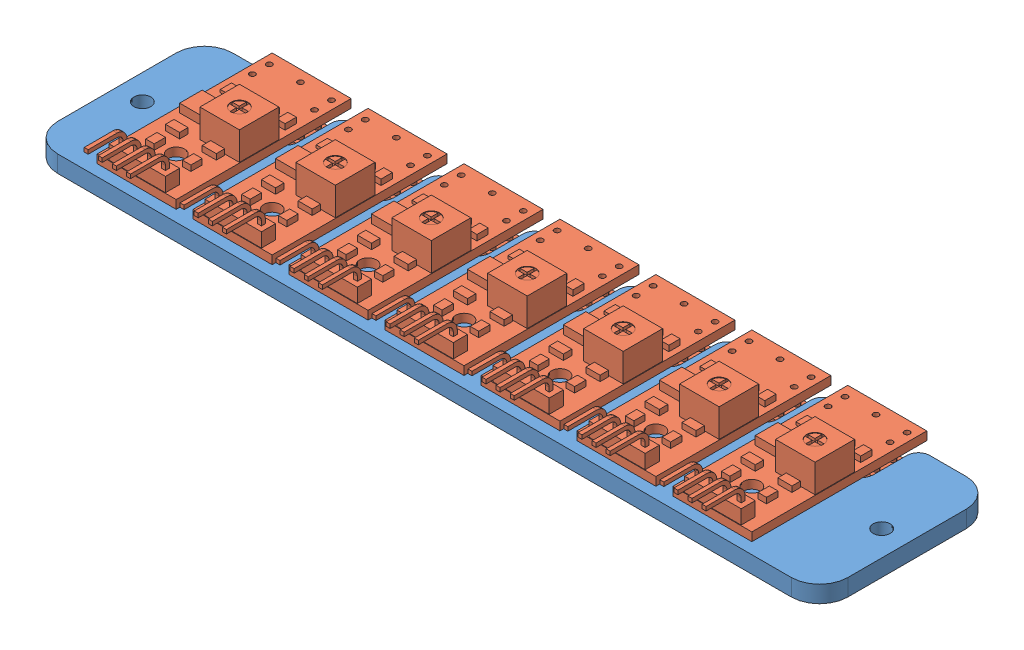
SolidWorks assembly test_sensor_base, configuration Default. Lengths in mm.
Overall size (140 34.84 41.36).
8 component instances, 2 part files, 3 mates.
Components (placement in the parent):
- base_sensor-1: base_sensor [Default] at (34.053 70.8746 117.5341) size (140 3 31)
- TCRT5000mod-1: TCRT5000mod [Default] at (-9.947 77.4833 127.859) x (0 -0.850182 0.526489) z (-1 0 0) size (17.6 37.76 14)
- TCRT5000mod-2: TCRT5000mod [Default] at (7.053 77.4833 127.859) x (0 -0.850182 0.526489) z (-1 0 0) size (17.6 37.76 14)
- TCRT5000mod-3: TCRT5000mod [Default] at (24.053 77.4833 127.859) x (0 -0.850182 0.526489) z (-1 0 0) size (17.6 37.76 14)
- TCRT5000mod-4: TCRT5000mod [Default] at (41.053 77.4833 127.859) x (0 -0.850182 0.526489) z (-1 0 0) size (17.6 37.76 14)
- TCRT5000mod-5: TCRT5000mod [Default] at (58.053 77.4833 127.859) x (0 -0.850182 0.526489) z (-1 0 0) size (17.6 37.76 14)
- TCRT5000mod-6: TCRT5000mod [Default] at (75.053 77.4833 127.859) x (0 -0.850182 0.526489) z (-1 0 0) size (17.6 37.76 14)
- TCRT5000mod-7: TCRT5000mod [Default] at (92.053 77.4833 127.859) x (0 -0.850182 0.526489) z (-1 0 0) size (17.6 37.76 14)
Mates (geometry in assembly coordinates):
- Concentric1: concentric anti-aligned: cylinder of base_sensor-1 through (-16.947 73.8746 126.0341) axis (0 -1 0) radius 1.5; circle of TCRT5000mod-1
- Parallel1: parallel anti-aligned: plane of base_sensor-1 through (-11.447 73.8746 110.0341) normal (-1 0 0); plane of TCRT5000mod-1 through (-9.947 77.3746 133.0341) normal (1 0 0)
- Distance1: distance = 2 mm anti-aligned: plane of TCRT5000mod-1 through (-9.947 75.8746 133.0341) normal (0 -1 0); plane of base_sensor-1 through (-20.447 73.8746 110.0341) normal (0 1 0)
